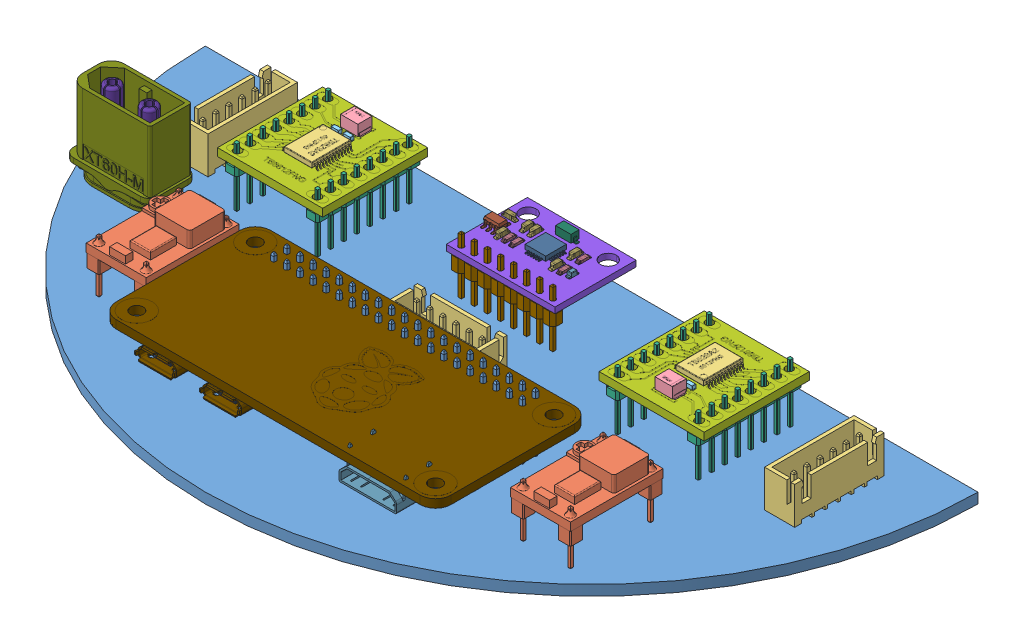
SolidWorks assembly PCB_assembly, configuration Default. Lengths in mm.
Overall size (150 19.55 75).
185 component instances, 39 part files, 22 mates.
Components (placement in the parent):
- PCB_Traces-1: PCB_Traces [Default] at origin size (150 2 75)
- dsn-mini-360-1: dsn-mini-360 [Default] at (-38.6821 8.33 44.6083) x (-1 0 0) z (0 1 0) size (11.65 18 12.03)
- dsn-mini-360-2: dsn-mini-360 [Default] at (43.5915 8.33 44.5295) x (-1 0 0) z (0 1 0) size (11.65 18 12.03)
- DOBLE PUENTE H-1: DOBLE PUENTE H [Default] at (37.9162 9.27 16.0693) x (0 0 1) z (0 1 0) size (20.51 20.4 12.06)
  - DOBLE PUENTE H.step-1: DOBLE PUENTE H.step [Default] at origin size (20.51 20.4 12.06)
    - TB6612FNG.step-1: TB6612FNG.step [Default] at (-1.0015 0.0048 1.75) x (-1 0 0) z (0 0 1) size (7.6 7 1.25)
    - capacitor.step-1: capacitor.step [Default] at (6.4979 -0.0001 1.6) x (0 -1 0) z (0 0 1) size (3.9 2.7 2.21)
    - capacitor_v1.step-1: capacitor_v1.step [Default] at (4 -1 1.53) x (0 -1 0) z (0 0 1) size (1.62 0.7 0.73)
    - capacitor_v1.step-2: capacitor_v1.step [Default] at (4 1.3 1.53) x (0 -1 0) z (0 0 1) size (1.62 0.7 0.73)
    - header_8.step-1: header_8.step [Default] at (8.9658 -7.83 -0.0056) x (0 1 0) z (-1 0 0) size (2.54 11.34 20.32)
    - header_8.step-2: header_8.step [Default] at (-9 7.67 0.07) x (0 -1 0) z (1 0 0) size (2.54 11.34 20.32)
    - DOBLE PUENTE H.step-1: DOBLE PUENTE H.step [Default] at origin size (20.4 20.4 1.5)
- DOBLE PUENTE H-2: DOBLE PUENTE H [Default] at (-36.7585 9.27 15.4667) x (0 0 -1) z (0 1 0) size (20.51 20.4 12.06)
  - DOBLE PUENTE H.step-1: DOBLE PUENTE H.step [Default] at origin size (20.51 20.4 12.06)
    - TB6612FNG.step-1: TB6612FNG.step [Default] at (-1.0015 0.0048 1.75) x (-1 0 0) z (0 0 1) size (7.6 7 1.25)
    - capacitor.step-1: capacitor.step [Default] at (6.4979 -0.0001 1.6) x (0 -1 0) z (0 0 1) size (3.9 2.7 2.21)
    - capacitor_v1.step-1: capacitor_v1.step [Default] at (4 -1 1.53) x (0 -1 0) z (0 0 1) size (1.62 0.7 0.73)
    - capacitor_v1.step-2: capacitor_v1.step [Default] at (4 1.3 1.53) x (0 -1 0) z (0 0 1) size (1.62 0.7 0.73)
    - header_8.step-1: header_8.step [Default] at (8.9658 -7.83 -0.0056) x (0 1 0) z (-1 0 0) size (2.54 11.34 20.32)
    - header_8.step-2: header_8.step [Default] at (-9 7.67 0.07) x (0 -1 0) z (1 0 0) size (2.54 11.34 20.32)
    - DOBLE PUENTE H.step-1: DOBLE PUENTE H.step [Default] at origin size (20.4 20.4 1.5)
- MPU 6050 IMU-1: MPU 6050 IMU [Default] at (8.2801 -1.7669 27.3967) x (-1 0 0) z (0 0 -1) size (21.11 11.18 15.88)
  - MPU 6050 IMU.STEP-1: MPU 6050 IMU.STEP [Default] at origin size (21.11 11.18 15.88)
    - Base.STEP-1: Base.STEP [Default] at (7.2489 10.9584 16.5726) size (21.11 1.14 15.75)
    - pin header.STEP-1: pin header.STEP [Default] at (16.0246 10.3869 9.8416) x (-1 0 0) z (0 0 1) size (2.54 11.18 2.54)
    - pin header.STEP-2: pin header.STEP [Default] at (13.4846 10.3869 9.8416) x (-1 0 0) z (0 0 1) size (2.54 11.18 2.54)
    - pin header.STEP-3: pin header.STEP [Default] at (10.9446 10.3869 9.8416) x (-1 0 0) z (0 0 1) size (2.54 11.18 2.54)
    - pin header.STEP-4: pin header.STEP [Default] at (8.4046 10.3869 9.8416) x (-1 0 0) z (0 0 1) size (2.54 11.18 2.54)
    - pin header.STEP-5: pin header.STEP [Default] at (5.8646 10.3869 9.8416) x (-1 0 0) z (0 0 1) size (2.54 11.18 2.54)
    - pin header.STEP-6: pin header.STEP [Default] at (3.3246 10.3869 9.8416) x (-1 0 0) z (0 0 1) size (2.54 11.18 2.54)
    - pin header.STEP-7: pin header.STEP [Default] at (0.7846 10.3869 9.8416) x (-1 0 0) z (0 0 1) size (2.54 11.18 2.54)
    - pin header.STEP-8: pin header.STEP [Default] at (-1.7554 10.3869 9.8416) x (-1 0 0) z (0 0 1) size (2.54 11.18 2.54)
    - sensor chip.STEP-1: sensor chip.STEP [Default] at (7.2489 11.5499 17.4466) size (5.4 0.9 5.4)
    - S2NH chip.STEP-1: S2NH chip.STEP [Default] at (16.1026 12.3799 16.5726) size (3 1.35 3.65)
    - Resistor small.STEP-1: Resistor small.STEP [Default] at (16.1026 11.5314 19.3726) size (2.75 0.94 0.95)
    - Resistor small.STEP-2: Resistor small.STEP [Default] at (13.9776 11.5314 15.6976) x (0 0 -1) z (1 0 0) size (2.75 0.94 0.95)
    - Resistor small black.STEP-1: Resistor small black.STEP [Default] at (12.6276 11.5299 15.6976) x (0 0 1) z (-1 0 0) size (2.45 0.54 0.95)
    - Resistor small black.STEP-2: Resistor small black.STEP [Default] at (11.1276 11.5299 15.6976) x (0 0 1) z (-1 0 0) size (2.45 0.54 0.95)
    - Resistor small.STEP-3: Resistor small.STEP [Default] at (12.6276 11.5314 19.3216) x (0 0 -1) z (1 0 0) size (2.75 0.94 0.95)
    - Resistor small.STEP-4: Resistor small.STEP [Default] at (11.1276 11.5314 19.3216) x (0 0 -1) z (1 0 0) size (2.75 0.94 0.95)
    - Resistor small.STEP-5: Resistor small.STEP [Default] at (3.3702 11.5314 19.3216) x (0 0 -1) z (1 0 0) size (2.75 0.94 0.95)
    - Resistor small black.STEP-3: Resistor small black.STEP [Default] at (1.8702 11.5299 15.6968) x (0 0 -1) z (1 0 0) size (2.45 0.54 0.95)
    - Resistor small.STEP-6: Resistor small.STEP [Default] at (3.3702 11.5314 15.6976) x (0 0 1) z (-1 0 0) size (2.75 0.94 0.95)
    - Small LED.STEP-1: Small LED.STEP [Default] at (0.3652 11.5299 15.6976) size (0.85 0.84 1.9)
    - Resistor small black.STEP-4: Resistor small black.STEP [Default] at (1.8702 11.5299 19.3216) x (0 0 1) z (-1 0 0) size (2.45 0.54 0.95)
    - Resistor black.STEP-1: Resistor black.STEP [Default] at (7.2489 12.3799 21.6466) size (4.2 1.6 1.6)
- XT60H-M v6-1: XT60H-M v6 [Default] at (-57.989 1.75 31.4786) x (1 0 0) z (0 1 0) size (16.55 9.35 19.55)
  - XT60H-M v6.step-1: XT60H-M v6.step [Default] at origin size (16.55 9.35 19.55)
    - Housing.step-1: Housing.step [Default] at origin size (16.55 9.35 15.8)
    - Contact.step-1: Contact.step [Default] at origin size (4.27 4.27 19.36)
    - Contact.step-2: Contact.step [Default] x (-1 0 0) z (0 0 1) size (4.27 4.27 19.36)
- Raspberry PI Zero W-1: Raspberry PI Zero W [Default] at (34.3323 10.98 64.6256) x (-1 0 0) z (0 -1 0) size (65 30.65 11.38)
  - Raspberry PI Zero W.step-1: Raspberry PI Zero W.step [Default] at origin size (65 32.42 20.3)
    - micro_usb_connector v17.step-1: micro_usb_connector v17.step [Default] at (41.4 3 1.74) x (0 -1 0) z (0 0 1) size (5.84 7.77 3.4)
      - shield.step-1: shield.step [Default] at origin size (5.84 7.77 3.4)
      - socket_housing.step-1: socket_housing.step [Default] at origin size (4.25 6.85 2.15)
      - socket_plate.step-1: socket_plate.step [Default] at origin size (3.38 6.8 0.31)
      - terminal.step-1: terminal.step [Default] at origin size (3.22 0.35 1.72)
      - terminal.step-2: terminal.step [Default] at (0 -1.3 0) size (3.22 0.35 1.72)
      - terminal.step-3: terminal.step [Default] at (0 -0.65 0) size (3.22 0.35 1.72)
      - terminal.step-4: terminal.step [Default] at (0 0.65 0) size (3.22 0.35 1.72)
      - terminal.step-5: terminal.step [Default] at (0 1.3 0) size (3.22 0.35 1.72)
    - micro_usb_connector v17.step-2: micro_usb_connector v17.step [Default] at (54 3 1.74) x (0 -1 0) z (0 0 1) size (5.84 7.77 3.4)
      - shield.step-1: shield.step [Default] at origin size (5.84 7.77 3.4)
      - socket_housing.step-1: socket_housing.step [Default] at origin size (4.25 6.85 2.15)
      - socket_plate.step-1: socket_plate.step [Default] at origin size (3.38 6.8 0.31)
      - terminal.step-1: terminal.step [Default] at origin size (3.22 0.35 1.72)
      - terminal.step-2: terminal.step [Default] at (0 -1.3 0) size (3.22 0.35 1.72)
      - terminal.step-3: terminal.step [Default] at (0 -0.65 0) size (3.22 0.35 1.72)
      - terminal.step-4: terminal.step [Default] at (0 0.65 0) size (3.22 0.35 1.72)
      - terminal.step-5: terminal.step [Default] at (0 1.3 0) size (3.22 0.35 1.72)
    - Components.step-1: Components.step [Default] at origin size (59.43 22.49 1.8)
      - CAPC-0402-T0.55-BN.step-1: CAPC-0402-T0.55-BN.step [Default] at (33.3698 17.6201 1.6) size (1.05 0.55 0.55)
      - CAPC-0402-T0.55-BN.step-2: CAPC-0402-T0.55-BN.step [Default] at (33.3698 16.6201 1.6) size (1.05 0.55 0.55)
      - CAPC-0402-T0.55-BN.step-3: CAPC-0402-T0.55-BN.step [Default] at (33.3698 15.6201 1.6) size (1.05 0.55 0.55)
      - CAPC-0402-T0.55-BN.step-4: CAPC-0402-T0.55-BN.step [Default] at (33.3698 14.6201 1.6) size (1.05 0.55 0.55)
      - CAPC-0402-T0.55-BN.step-5: CAPC-0402-T0.55-BN.step [Default] at (33.3698 13.6201 1.6) size (1.05 0.55 0.55)
      - CAPC-0402-T0.55-BN.step-6: CAPC-0402-T0.55-BN.step [Default] at (33.3698 12.6201 1.6) size (1.05 0.55 0.55)
      - CAPC-0402-T0.55-BN.step-7: CAPC-0402-T0.55-BN.step [Default] at (33.3698 11.6201 1.6) size (1.05 0.55 0.55)
      - CAPC-0402-T0.55-BN.step-8: CAPC-0402-T0.55-BN.step [Default] at (35.2975 17.3433 1.6) x (0 -1 0) z (0 0 1) size (1.05 0.55 0.55)
      - CAPC-0402-T0.55-BN.step-9: CAPC-0402-T0.55-BN.step [Default] at (35.2975 15.5933 1.6) x (0 -1 0) z (0 0 1) size (1.05 0.55 0.55)
      - CAPC-0402-T0.55-BN.step-10: CAPC-0402-T0.55-BN.step [Default] at (20.7555 5.9273 1.6) x (0 -1 0) z (0 0 1) size (1.05 0.55 0.55)
      - CAPC-0402-T0.55-BN.step-11: CAPC-0402-T0.55-BN.step [Default] at (21.5605 5.9273 1.6) x (0 -1 0) z (0 0 1) size (1.05 0.55 0.55)
      - CAPC-0402-T0.55-BN.step-12: CAPC-0402-T0.55-BN.step [Default] at (22.3655 5.9273 1.6) x (0 -1 0) z (0 0 1) size (1.05 0.55 0.55)
      - CAPC-0402-T0.55-BN.step-13: CAPC-0402-T0.55-BN.step [Default] at (23.1705 5.9273 1.6) x (0 -1 0) z (0 0 1) size (1.05 0.55 0.55)
      - CAPC-0402-T0.55-BN.step-14: CAPC-0402-T0.55-BN.step [Default] at (23.9755 5.9273 1.6) x (0 -1 0) z (0 0 1) size (1.05 0.55 0.55)
      - CAPC-0402-T0.55-BN.step-15: CAPC-0402-T0.55-BN.step [Default] at (24.7805 5.9273 1.6) x (0 -1 0) z (0 0 1) size (1.05 0.55 0.55)
      - CAPC-0402-T0.55-BN.step-16: CAPC-0402-T0.55-BN.step [Default] at (25.5855 5.9273 1.6) x (0 -1 0) z (0 0 1) size (1.05 0.55 0.55)
      - CAPC-0402-T0.55-BN.step-17: CAPC-0402-T0.55-BN.step [Default] at (26.3905 5.9273 1.6) x (0 -1 0) z (0 0 1) size (1.05 0.55 0.55)
      - CAPC-0402-T0.55-BN.step-18: CAPC-0402-T0.55-BN.step [Default] at (27.1955 5.9273 1.6) x (0 -1 0) z (0 0 1) size (1.05 0.55 0.55)
      - CAPC-0402-T0.55-BN.step-19: CAPC-0402-T0.55-BN.step [Default] at (28.0005 5.9273 1.6) x (0 -1 0) z (0 0 1) size (1.05 0.55 0.55)
      - CAPC-0402-T0.55-BN.step-20: CAPC-0402-T0.55-BN.step [Default] at (34.1 10.6 1.6) size (1.05 0.55 0.55)
      - CAPC-0402-T0.55-BN.step-21: CAPC-0402-T0.55-BN.step [Default] at (34.1 9.79 1.6) size (1.05 0.55 0.55)
      - CAPC-0402-T0.55-BN.step-22: CAPC-0402-T0.55-BN.step [Default] at (34.1 8.98 1.6) size (1.05 0.55 0.55)
      - CAPC-0402-T0.55-BN.step-23: CAPC-0402-T0.55-BN.step [Default] at (34.1 8.17 1.6) size (1.05 0.55 0.55)
      - CAPC-0402-T0.55-BN.step-24: CAPC-0402-T0.55-BN.step [Default] at (34.1 7.36 1.6) size (1.05 0.55 0.55)
      - CAPC-0402-T0.55-BN.step-25: CAPC-0402-T0.55-BN.step [Default] at (17.4437 19.1633 1.6) size (1.05 0.55 0.55)
      - CAPC-0402-T0.55-BN.step-26: CAPC-0402-T0.55-BN.step [Default] at (17.4437 18.1633 1.6) size (1.05 0.55 0.55)
      - CAPC-0402-T0.55-BN.step-27: CAPC-0402-T0.55-BN.step [Default] at (17.4437 17.1633 1.6) size (1.05 0.55 0.55)
      - CAPC-0402-T0.55-BN.step-28: CAPC-0402-T0.55-BN.step [Default] at (17.4437 16.1633 1.6) size (1.05 0.55 0.55)
      - CAPC-0402-T0.55-BN.step-29: CAPC-0402-T0.55-BN.step [Default] at (17.4437 15.1633 1.6) size (1.05 0.55 0.55)
      - CAPC-0402-T0.55-BN.step-30: CAPC-0402-T0.55-BN.step [Default] at (17.9697 14.164 1.6) size (1.05 0.55 0.55)
      - CAPC-0402-T0.55-BN.step-31: CAPC-0402-T0.55-BN.step [Default] at (17.9697 13.344 1.6) size (1.05 0.55 0.55)
      - CAPC-0402-T0.55-BN.step-32: CAPC-0402-T0.55-BN.step [Default] at (31.3668 5.5372 1.6) size (1.05 0.55 0.55)
      - CAPC-0402-T0.55-BN.step-33: CAPC-0402-T0.55-BN.step [Default] at (36.2259 10.107 1.6) x (0 -1 0) z (0 0 1) size (1.05 0.55 0.55)
      - CAPC-0402-T0.55-BN.step-34: CAPC-0402-T0.55-BN.step [Default] at (30.8759 20.015 1.6) size (1.05 0.55 0.55)
      - CAPC-0402-T0.55-BN.step-35: CAPC-0402-T0.55-BN.step [Default] at (25.6574 20.7007 1.6) x (0 -1 0) z (0 0 1) size (1.05 0.55 0.55)
      - CAPC-0402-T0.55-BN.step-36: CAPC-0402-T0.55-BN.step [Default] at (24.6574 20.7007 1.6) x (0 -1 0) z (0 0 1) size (1.05 0.55 0.55)
      - CAPC-0402-T0.55-BN.step-37: CAPC-0402-T0.55-BN.step [Default] at (23.6574 20.7007 1.6) x (0 -1 0) z (0 0 1) size (1.05 0.55 0.55)
      - CAPC-0402-T0.55-BN.step-38: CAPC-0402-T0.55-BN.step [Default] at (20.2103 20.6923 1.6) x (0 -1 0) z (0 0 1) size (1.05 0.55 0.55)
      - CAPC-0402-T0.55-BN.step-39: CAPC-0402-T0.55-BN.step [Default] at (39.0204 12.9386 1.6) size (1.05 0.55 0.55)
      - CAPC-0402-T0.55-BN.step-40: CAPC-0402-T0.55-BN.step [Default] at (40.6631 15.6901 1.6) size (1.05 0.55 0.55)
      - CAPC-0402-T0.55-BN.step-41: CAPC-0402-T0.55-BN.step [Default] at (39.3678 16.5618 1.6) size (1.05 0.55 0.55)
      - CAPC-0402-T0.55-BN.step-42: CAPC-0402-T0.55-BN.step [Default] at (42.831 16.9675 1.6) x (0 -1 0) z (0 0 1) size (1.05 0.55 0.55)
      - CAPC-0402-T0.55-BN.step-43: CAPC-0402-T0.55-BN.step [Default] at (41.2678 16.5618 1.6) size (1.05 0.55 0.55)
      - CAPC-0402-T0.55-BN.step-44: CAPC-0402-T0.55-BN.step [Default] at (5.0529 7.1196 1.6) size (1.05 0.55 0.55)
      - CAPC-0402-T0.55-BN.step-45: CAPC-0402-T0.55-BN.step [Default] at (37.9324 22.363 1.6) size (1.05 0.55 0.55)
      - CAPC-0402-T0.55-BN.step-46: CAPC-0402-T0.55-BN.step [Default] at (52.706 14.1667 1.6) size (1.05 0.55 0.55)
      - CAPC-0603-T0.9-BN.step-1: CAPC-0603-T0.9-BN.step [Default] at (1.2622 8.8622 1.6) x (0 -1 0) z (0 0 1) size (1.7 0.9 0.9)
      - CAPC-0402-T0.55-BN.step-47: CAPC-0402-T0.55-BN.step [Default] at (19.3797 6.5002 1.6) size (1.05 0.55 0.55)
      - CAPC-0402-T0.55-BN.step-48: CAPC-0402-T0.55-BN.step [Default] at (19.3316 1.3043 1.6) size (1.05 0.55 0.55)
      - CAPC-0603-T0.9-BN.step-2: CAPC-0603-T0.9-BN.step [Default] at (33.8953 18.8389 1.6) size (1.7 0.9 0.9)
      - INDC-0603.step-1: INDC-0603.step [Default] at (39.8621 18.1224 1.6) size (1.75 0.95 0.95)
      - INDC-0603.step-2: INDC-0603.step [Default] at (39.1295 14.7453 1.6) x (0 -1 0) z (0 0 1) size (1.75 0.95 0.95)
      - INDC-0402.step-1: INDC-0402.step [Default] at (29.426 5.5149 1.6) size (1.05 0.55 0.55)
      - INDC-0402.step-2: INDC-0402.step [Default] at (41.7855 10.5602 1.6) size (1.05 0.55 0.55)
      - INDC-0402.step-3: INDC-0402.step [Default] at (41.7855 9.7502 1.6) size (1.05 0.55 0.55)
      - INDC-0402.step-4: INDC-0402.step [Default] at (46.2071 10.726 1.6) size (1.05 0.55 0.55)
      - INDC-0402.step-5: INDC-0402.step [Default] at (18.9188 8.3162 1.6) size (1.05 0.55 0.55)
      - INDC-0402.step-6: INDC-0402.step [Default] at (16.9188 8.3162 1.6) size (1.05 0.55 0.55)
      - CAPC-0805-T0.95-BN.step-1: CAPC-0805-T0.95-BN.step [Default] at (27.8612 20.5927 1.6) size (2.1 1.35 0.95)
      - CAPC-0805-T0.95-BN.step-2: CAPC-0805-T0.95-BN.step [Default] at (27.8612 22.8427 1.6) size (2.1 1.35 0.95)
      - CAPC-0805-T0.95-BN.step-3: CAPC-0805-T0.95-BN.step [Default] at (51.017 11.9186 1.6) x (0 -1 0) z (0 0 1) size (2.1 1.35 0.95)
      - CAPC-0805-T0.95-BN.step-4: CAPC-0805-T0.95-BN.step [Default] at (52.817 11.9186 1.6) x (0 -1 0) z (0 0 1) size (2.1 1.35 0.95)
      - CAPC-0805-T0.95-BN.step-5: CAPC-0805-T0.95-BN.step [Default] at (57.6691 12.6645 1.6) x (0 -1 0) z (0 0 1) size (2.1 1.35 0.95)
      - CAPC-0805-T0.95-BN.step-6: CAPC-0805-T0.95-BN.step [Default] at (59.5691 12.6645 1.6) x (0 -1 0) z (0 0 1) size (2.1 1.35 0.95)
      - CAPC-1206-T1.4-BN.step-1: CAPC-1206-T1.4-BN.step [Default] at (55.8544 7.8017 1.6) x (0 -1 0) z (0 0 1) size (3.35 1.75 1.4)
      - CAPC-0805-T0.95-BN.step-7: CAPC-0805-T0.95-BN.step [Default] at (47.3323 2.998 1.6) size (2.1 1.35 0.95)
      - RESC-0402.step-1: RESC-0402.step [Default] at (35.3052 13.8988 1.6) x (0 -1 0) z (0 0 1) size (1.05 0.55 0.4)
      - RESC-0402.step-2: RESC-0402.step [Default] at (35.3052 12.2988 1.6) x (0 -1 0) z (0 0 1) size (1.05 0.55 0.4)
      - RESC-0402.step-3: RESC-0402.step [Default] at (35.3713 10.1216 1.6) x (0 -1 0) z (0 0 1) size (1.05 0.55 0.4)
      - RESC-0402.step-4: RESC-0402.step [Default] at (14.6084 13.087 1.6) x (0 1 0) z (0 0 1) size (1.05 0.55 0.4)
      - RESC-0402.step-5: RESC-0402.step [Default] at (13.9844 22.5264 1.6) x (0 -1 0) z (0 0 1) size (1.05 0.55 0.4)
      - RESC-0402.step-6: RESC-0402.step [Default] at (15.3844 22.5264 1.6) x (0 -1 0) z (0 0 1) size (1.05 0.55 0.4)
      - RESC-0402.step-7: RESC-0402.step [Default] at (4.6621 10.2008 1.6) size (1.05 0.55 0.4)
      - RESC-0402.step-8: RESC-0402.step [Default] at (58.3516 9.0224 1.6) x (0 1 0) z (0 0 1) size (1.05 0.55 0.4)
      - RESC-0402.step-9: RESC-0402.step [Default] at (59.1516 9.0224 1.6) x (0 1 0) z (0 0 1) size (1.05 0.55 0.4)
      - RESC-0402.step-10: RESC-0402.step [Default] at (59.9516 9.0224 1.6) x (0 1 0) z (0 0 1) size (1.05 0.55 0.4)
      - RESC-0402.step-11: RESC-0402.step [Default] at (36.9521 21.579 1.6) size (1.05 0.55 0.4)
      - CAPC-0402-T0.55-BN.step-49: CAPC-0402-T0.55-BN.step [Default] at (30.8759 21.315 1.6) size (1.05 0.55 0.55)
      - RESC-0402.step-12: RESC-0402.step [Default] at (47.4882 18.8168 1.6) x (0.707107 0.707107 0) z (0 0 1) size (1.05 0.55 0.4)
      - RESC-0402.step-13: RESC-0402.step [Default] at (52.3627 20.1006 1.6) x (0 1 0) z (0 0 1) size (1.05 0.55 0.4)
      - RESC-0402.step-14: RESC-0402.step [Default] at (53.0236 15.6867 1.6) size (1.05 0.55 0.4)
      - SRN4018.step-1: SRN4018.step [Default] at (57.7919 17.1897 1.6) size (4.2 4.2 1.8)
      - Components-0.step-1: Components-0.step [Default] at origin size (12.01 12.01 1)
      - Components-1.step-1: Components-1.step [Default] at origin size (4.88 2.9 0.6)
    - Mini HDMI.step-1: Mini HDMI.step [Default] at (12.5 5.85 3.1) x (0 -1 0) z (0 0 1) size (16.55 11.21 19.45)
      - Housing.step-1: Housing.step [Default] at origin size (16.55 9.35 15.8) (hidden)
      - Shielding.step-1: Shielding.step [Default] at (2.875 0 0.82) x (0 1 0) z (0 0 1) size (11.21 7.6 5.45)
      - Housing2.step-1: Housing2.step [Default] at (-0.075 0 -0.65) x (0 -1 0) z (0 0 1) size (8.25 0.75 1.6)
      - Pin1.step-1: Pin1.step [Default] at (2.1 -3.6 0.3) size (5.9 0.15 1.8)
      - Pin1.step-2: Pin1.step [Default] at (2.1 -2.8 0.3) size (5.9 0.15 1.8)
      - Pin1.step-3: Pin1.step [Default] at (2.1 -2.4 0.3) size (5.9 0.15 1.8)
      - Pin1.step-4: Pin1.step [Default] at (2.1 -2 0.3) size (5.9 0.15 1.8)
      - Pin1.step-5: Pin1.step [Default] at (2.1 -1.6 0.3) size (5.9 0.15 1.8)
      - Pin1.step-6: Pin1.step [Default] at (2.1 -1.2 0.3) size (5.9 0.15 1.8)
      - Pin1.step-7: Pin1.step [Default] at (2.1 -0.8 0.3) size (5.9 0.15 1.8)
      - Pin1.step-8: Pin1.step [Default] at (2.1 -0.4 0.3) size (5.9 0.15 1.8)
      - Pin1.step-9: Pin1.step [Default] at (2.1 0 0.3) size (5.9 0.15 1.8)
      - Pin1.step-10: Pin1.step [Default] at (2.1 0.4 0.3) size (5.9 0.15 1.8)
      - Pin1.step-11: Pin1.step [Default] at (2.1 0.8 0.3) size (5.9 0.15 1.8)
      - Pin1.step-12: Pin1.step [Default] at (2.1 1.2 0.3) size (5.9 0.15 1.8)
      - Pin1.step-13: Pin1.step [Default] at (2.1 1.6 0.3) size (5.9 0.15 1.8)
      - Pin1.step-14: Pin1.step [Default] at (2.1 2 0.3) size (5.9 0.15 1.8)
      - Pin1.step-15: Pin1.step [Default] at (2.1 2.4 0.3) size (5.9 0.15 1.8)
      - Pin1.step-16: Pin1.step [Default] at (2.1 2.8 0.3) size (5.9 0.15 1.8)
      - Pin1.step-17: Pin1.step [Default] at (2.1 3.2 0.3) size (5.9 0.15 1.8)
      - Pin1.step-18: Pin1.step [Default] at (2.1 3.6 0.3) size (5.9 0.15 1.8)
      - Pin2.step-1: Pin2.step [Default] at (1.7983 -3.2 0.3) size (5.3 0.15 1.8)
    - Board.step-1: Board.step [Default] at origin size (65 30 1.62)
    - HDRV40W64P254_2X20_5080X508X838B.step-1: HDRV40W64P254_2X20_5080X508X838B.step [Default] at (8.37 27.77 1.6) size (50.8 5.08 11.38)
    - Micro SD slot.step-1: Micro SD slot.step [Default] at (7.3191 16.9624 1.57) x (0 -1 0) z (-1 0 0) size (11.95 1.45 11.4)
- JST - XH - Thru (V) - 6Pin - 2.54mm-1: JST - XH - Thru (V) - 6Pin - 2.54mm [Default] at (60.6417 1 15.0333) x (0 0 -1) z (0 1 0) size (17.37 5.84 10.21)
- JST - XH - Thru (V) - 6Pin - 2.54mm-2: JST - XH - Thru (V) - 6Pin - 2.54mm [Default] at (1.4368 1 29.0395) x (-1 0 0) z (0 1 0) size (17.37 5.84 10.21)
- JST - XH - Thru (V) - 6Pin - 2.54mm-3: JST - XH - Thru (V) - 6Pin - 2.54mm [Default] at (-56.0757 1 13.0614) x (0 0 1) z (0 1 0) size (17.37 5.84 10.21)
Mates (geometry in assembly coordinates):
- Parallel1: parallel: plane of PCB_Traces-1 through (0 1 0) normal (0 1 0); plane of dsn-mini-360-1 through (-38.6821 8.33 44.6083) normal (0 -1 0)
- Parallel2: parallel: plane of PCB_Traces-1 through (-75 1 0) normal (0 0 -1); plane of dsn-mini-360-1 through (-48.2427 9.93 53.6083) normal (0 0 1)
- Coincident3: coincident: plane of PCB_Traces-1 through (0 1 0) normal (0 1 0); line of dsn-mini-360-1 through (-43.3571 1 52.4333) axis (0 0 -1)
- Parallel3: parallel: plane of PCB_Traces-1 through (0 1 0) normal (0 1 0); plane of dsn-mini-360-2 through (43.5915 8.33 44.5295) normal (0 -1 0)
- Parallel4: parallel: plane of PCB_Traces-1 through (-75 1 0) normal (0 0 -1); plane of dsn-mini-360-2 through (34.0309 9.93 53.5295) normal (0 0 1)
- Coincident6: coincident: plane of PCB_Traces-1 through (0 1 0) normal (0 1 0); line of dsn-mini-360-2 through (48.2665 1 36.7045) axis (0 0 1)
- Parallel5: parallel: plane of PCB_Traces-1 through (0 1 0) normal (0 1 0); plane of DOBLE PUENTE H-1/DOBLE PUENTE H.step-1/DOBLE PUENTE H.step-1 through (37.9162 9.27 16.0693) normal (0 -1 0)
- Parallel6: parallel: plane of PCB_Traces-1 through (-75 1 0) normal (0 0 -1); plane of DOBLE PUENTE H-1/DOBLE PUENTE H.step-1/DOBLE PUENTE H.step-1 through (48.1162 9.27 5.8693) normal (0 0 -1)
- Coincident9: coincident: plane of PCB_Traces-1 through (0 1 0) normal (0 1 0); line of DOBLE PUENTE H-1/DOBLE PUENTE H.step-1/header_8.step-2 through (45.8062 1 6.7493) axis (0.707107 0 0.707107)
- Coincident10: coincident: plane of PCB_Traces-1 through (0 1 0) normal (0 1 0); plane of DOBLE PUENTE H-2/DOBLE PUENTE H.step-1/header_8.step-2 through (-44.4285 1 24.4667) normal (0 -1 0)
- Parallel7: parallel anti-aligned: plane of PCB_Traces-1 through (-75 1 0) normal (0 0 -1); plane of DOBLE PUENTE H-2/DOBLE PUENTE H.step-1/DOBLE PUENTE H.step-1 through (-46.9585 9.27 25.6667) normal (0 0 1)
- Coincident12: coincident: plane of PCB_Traces-1 through (0 1 0) normal (0 1 0); plane of MPU 6050 IMU-1/MPU 6050 IMU.STEP-1/pin header.STEP-1 through (-7.7445 1 17.5551) normal (0 -1 0)
- Parallel8: parallel anti-aligned: plane of PCB_Traces-1 through (-75 1 0) normal (0 0 -1); plane of MPU 6050 IMU-1/MPU 6050 IMU.STEP-1/Base.STEP-1 through (11.5849 9.763 18.6981) normal (0 0 1)
- Coincident14: coincident anti-aligned: plane of PCB_Traces-1 through (0 1 0) normal (0 1 0); plane of XT60H-M v6-1/XT60H-M v6.step-1/Contact.step-2 through (-61.589 1 31.4786) normal (0 -1 0)
- Coincident16: coincident: plane of PCB_Traces-1 through (0 1 0) normal (0 1 0); plane of Raspberry PI Zero W-1/Raspberry PI Zero W.step-1/HDRV40W64P254_2X20_5080X508X838B.step-1 through (23.4223 1 36.8556) normal (0 -1 0)
- Parallel9: parallel aligned: plane of PCB_Traces-1 through (-75 1 0) normal (0 0 -1); plane of Raspberry PI Zero W-1/Raspberry PI Zero W.step-1/Board.step-1 through (-27.6677 10.98 34.6256) normal (0 0 -1)
- Coincident18: coincident: plane of PCB_Traces-1 through (0 1 0) normal (0 1 0); plane of JST - XH - Thru (V) - 6Pin - 2.54mm-1 through (60.6417 1 15.0333) normal (0 -1 0)
- Parallel10: parallel aligned: plane of PCB_Traces-1 through (-75 1 0) normal (0 0 -1); plane of JST - XH - Thru (V) - 6Pin - 2.54mm-1 through (57.2889 1.7112 6.3465) normal (0 0 -1)
- Coincident20: coincident: plane of PCB_Traces-1 through (0 1 0) normal (0 1 0); plane of JST - XH - Thru (V) - 6Pin - 2.54mm-2 through (1.4368 1 29.0395) normal (0 -1 0)
- Parallel11: parallel anti-aligned: plane of PCB_Traces-1 through (-75 1 0) normal (0 0 -1); plane of JST - XH - Thru (V) - 6Pin - 2.54mm-2 through (10.1236 1.7112 32.3923) normal (0 0 1)
- Coincident22: coincident: plane of PCB_Traces-1 through (0 1 0) normal (0 1 0); plane of JST - XH - Thru (V) - 6Pin - 2.54mm-3 through (-56.0757 1 13.0614) normal (0 -1 0)
- Parallel12: parallel aligned: plane of PCB_Traces-1 through (-75 1 0) normal (0 0 -1); plane of JST - XH - Thru (V) - 6Pin - 2.54mm-3 through (-58.5649 1.7112 4.3746) normal (0 0 -1)
